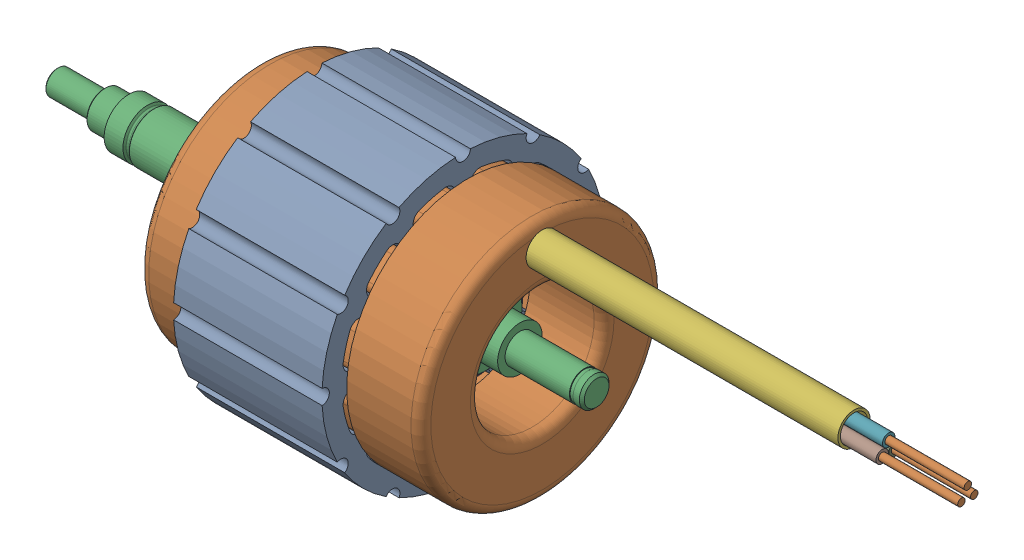
SolidWorks assembly MotorAssy_v1, configuration Default. Lengths in mm.
Overall size (184 56.92 56.92).
9 component instances, 6 part files, 11 mates.
Components (placement in the parent):
- Stator-1: Stator [Default] at (2.5 0 0) size (30 56.92 56.92)
- Wind_Test_v1-1: Wind_Test_v1 [Default] at (32.5 0 0) x (-1 0 0) z (0 0 -1) size (143 49 49)
- Shaft-1: Shaft [Default] at origin size (109 18.8 18.8)
- Permanent_Magnet_Arc-1: Permanent_Magnet_Arc [Default] at (17.5 0 0) size (35 3.95 12.55)
- CFRP-Rotor-Sleeve-1: CFRP-Rotor-Sleeve [Default] at (-2 0 0) size (37 19.2 19.2)
- Cable-Isolation-1: Cable-Isolation [Default] at (48.5 19.7506 0) x (0 0.866025 0.5) z (0 0.5 -0.866025) size (6.5 70 6.5)
- Permanent_Magnet_Arc-2: Permanent_Magnet_Arc [Default] at (17.5 0 0) x (1 0 0) z (0 -1 0) size (35 3.95 12.55)
- Permanent_Magnet_Arc-3: Permanent_Magnet_Arc [Default] at (17.5 0 0) x (1 0 0) z (0 0 -1) size (35 3.95 12.55)
- Permanent_Magnet_Arc-4: Permanent_Magnet_Arc [Default] at (17.5 0 0) x (1 0 0) z (0 1 0) size (35 3.95 12.55)
Mates (geometry in assembly coordinates):
- Concentric9: concentric anti-aligned: cylinder of Stat_Test_v1-1 through (32.5 0 0) axis (-1 0 0) radius 28.5; cylinder of Shaft-1 through (88.99 0 0) axis (1 0 0) radius 7.42
- Concentric10: concentric anti-aligned: cylinder of Stat_Test_v1-1 through (32.5 0 0) axis (-1 0 0) radius 28.5; cylinder of Wind_Test_v1-1 through (34.5 0 0) axis (1 0 0) radius 24.5
- Distance3: distance = 1 mm anti-aligned: plane of Stat_Test_v1-1 through (32.5 0 0) normal (1 0 0); plane of Wind_Test_v1-1 through (33.5 24.5 0) normal (-1 0 0)
- Concentric11: concentric anti-aligned: cylinder of Shaft-1 through (88.99 0 0) axis (1 0 0) radius 7.42; cylinder of Permanent_Magnet_Arc-1 through (35 0 0) axis (-1 0 0) radius 9.4
- Coincident5: coincident anti-aligned: plane of Shaft-1 through (0 9.4 0) normal (1 0 0); plane of Permanent_Magnet_Arc-1 through (0 6.8862 6.0251) normal (-1 0 0)
- Distance6: distance = 2.5 mm anti-aligned: plane of Stat_Test_v1-1 through (2.5 0 0) normal (-1 0 0); plane of Shaft-1 through (0 9.4 0) normal (1 0 0)
- Concentric12: concentric aligned: cylinder of Shaft-1 through (88.99 0 0) axis (1 0 0) radius 3; cylinder of CFRP-Rotor-Sleeve-1 through (86.99 0 0) axis (1 0 0) radius 9.6
- Coincident6: coincident aligned: plane of Shaft-1 through (-2 6.5 0) normal (-1 0 0); plane of CFRP-Rotor-Sleeve-1 through (-2 9.6 0) normal (-1 0 0)
- Coincident8: coincident anti-aligned: plane of Wind_Test_v1-1 through (48.5 22.5 0) normal (1 0 0); plane of Cable-Isolation-1 through (48.5 19.7506 0) normal (-1 0 0)
- Concentric17: concentric aligned: cylinder of Wind_Test_v1-1 through (134.5 21.2517 0) axis (-1 0 0) radius 0.75; cylinder of Cable-Isolation-1 through (118.5 21.2517 0) axis (-1 0 0) radius 1.25
- Concentric18: concentric aligned: cylinder of Wind_Test_v1-1 through (134.5 19 -1.3) axis (-1 0 0) radius 0.75; cylinder of Cable-Isolation-1 through (118.5 19 -1.3) axis (-1 0 0) radius 1.25
